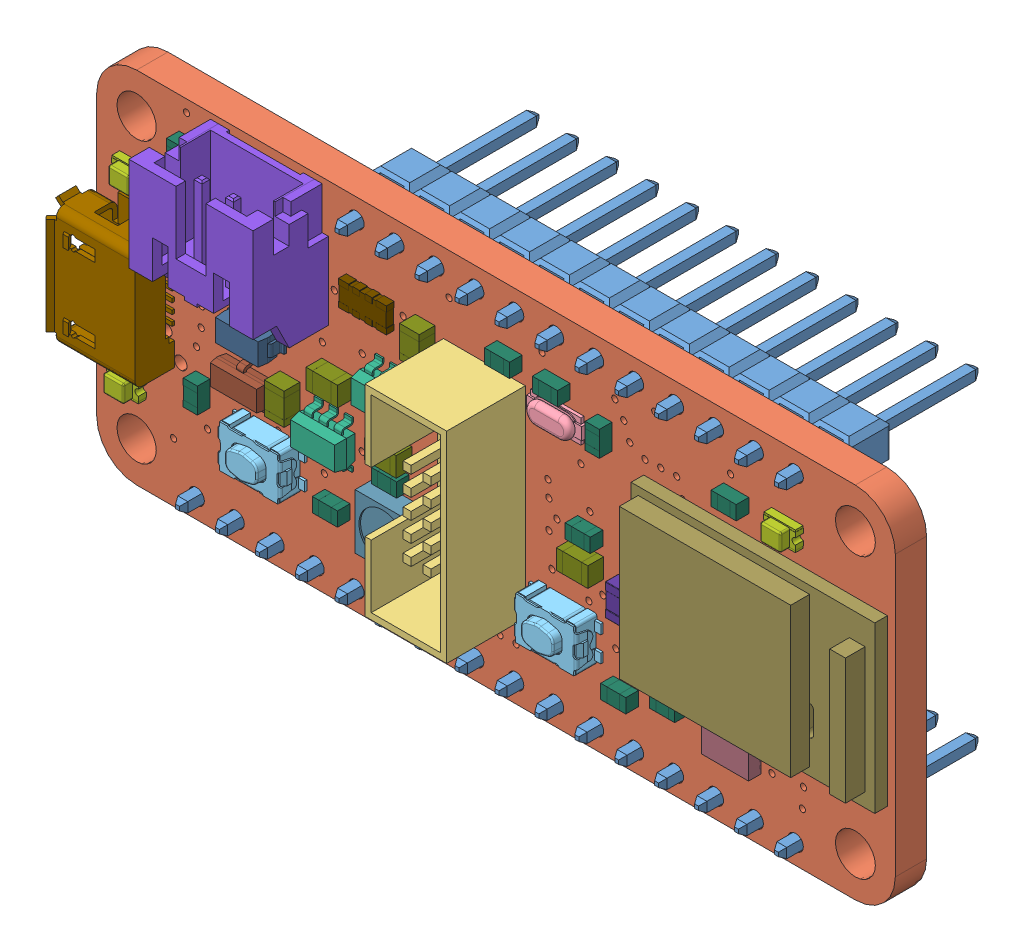
SolidWorks assembly nRF52840 Feather, configuration Default. Lengths in mm.
Overall size (51.45 22.86 16.48).
65 component instances, 18 part files, 10 mates.
Components (placement in the parent):
- Pin Header 1x1 TH Pitch 2.54mm^nRF52840 Feather-1: Pin Header 1x1 TH Pitch 2.54mm^nRF52840 Feather [Default] at (6.35 1.27 0.0014) x (0 1 0) z (0 0 -1) size (2.54 2.54 12.7) (virtual)
- Pin Header 1x1 TH Pitch 2.54mm^nRF52840 Feather-56: Pin Header 1x1 TH Pitch 2.54mm^nRF52840 Feather [Default] at (8.89 1.27 0.0014) x (0 1 0) z (0 0 -1) size (2.54 2.54 12.7) (virtual)
- Pin Header 1x1 TH Pitch 2.54mm^nRF52840 Feather-57: Pin Header 1x1 TH Pitch 2.54mm^nRF52840 Feather [Default] at (11.43 1.27 0.0014) x (0 1 0) z (0 0 -1) size (2.54 2.54 12.7) (virtual)
- Pin Header 1x1 TH Pitch 2.54mm^nRF52840 Feather-58: Pin Header 1x1 TH Pitch 2.54mm^nRF52840 Feather [Default] at (13.97 1.27 0.0014) x (0 1 0) z (0 0 -1) size (2.54 2.54 12.7) (virtual)
- Pin Header 1x1 TH Pitch 2.54mm^nRF52840 Feather-59: Pin Header 1x1 TH Pitch 2.54mm^nRF52840 Feather [Default] at (16.51 1.27 0.0014) x (0 1 0) z (0 0 -1) size (2.54 2.54 12.7) (virtual)
- Pin Header 1x1 TH Pitch 2.54mm^nRF52840 Feather-60: Pin Header 1x1 TH Pitch 2.54mm^nRF52840 Feather [Default] at (19.05 1.27 0.0014) x (0 1 0) z (0 0 -1) size (2.54 2.54 12.7) (virtual)
- Pin Header 1x1 TH Pitch 2.54mm^nRF52840 Feather-61: Pin Header 1x1 TH Pitch 2.54mm^nRF52840 Feather [Default] at (21.59 1.27 0.0014) x (0 1 0) z (0 0 -1) size (2.54 2.54 12.7) (virtual)
- Pin Header 1x1 TH Pitch 2.54mm^nRF52840 Feather-62: Pin Header 1x1 TH Pitch 2.54mm^nRF52840 Feather [Default] at (24.13 1.27 0.0014) x (0 1 0) z (0 0 -1) size (2.54 2.54 12.7) (virtual)
- Pin Header 1x1 TH Pitch 2.54mm^nRF52840 Feather-63: Pin Header 1x1 TH Pitch 2.54mm^nRF52840 Feather [Default] at (26.67 1.27 0.0014) x (0 1 0) z (0 0 -1) size (2.54 2.54 12.7) (virtual)
- Pin Header 1x1 TH Pitch 2.54mm^nRF52840 Feather-64: Pin Header 1x1 TH Pitch 2.54mm^nRF52840 Feather [Default] at (29.21 1.27 0.0014) x (0 1 0) z (0 0 -1) size (2.54 2.54 12.7) (virtual)
- Pin Header 1x1 TH Pitch 2.54mm^nRF52840 Feather-65: Pin Header 1x1 TH Pitch 2.54mm^nRF52840 Feather [Default] at (31.75 1.27 0.0014) x (0 1 0) z (0 0 -1) size (2.54 2.54 12.7) (virtual)
- Pin Header 1x1 TH Pitch 2.54mm^nRF52840 Feather-66: Pin Header 1x1 TH Pitch 2.54mm^nRF52840 Feather [Default] at (34.29 1.27 0.0014) x (0 1 0) z (0 0 -1) size (2.54 2.54 12.7) (virtual)
- Pin Header 1x1 TH Pitch 2.54mm^nRF52840 Feather-67: Pin Header 1x1 TH Pitch 2.54mm^nRF52840 Feather [Default] at (36.83 1.27 0.0014) x (0 1 0) z (0 0 -1) size (2.54 2.54 12.7) (virtual)
- Pin Header 1x1 TH Pitch 2.54mm^nRF52840 Feather-68: Pin Header 1x1 TH Pitch 2.54mm^nRF52840 Feather [Default] at (39.37 1.27 0.0014) x (0 1 0) z (0 0 -1) size (2.54 2.54 12.7) (virtual)
- Pin Header 1x1 TH Pitch 2.54mm^nRF52840 Feather-69: Pin Header 1x1 TH Pitch 2.54mm^nRF52840 Feather [Default] at (41.91 1.27 0.0014) x (0 1 0) z (0 0 -1) size (2.54 2.54 12.7) (virtual)
- Pin Header 1x1 TH Pitch 2.54mm^nRF52840 Feather-70: Pin Header 1x1 TH Pitch 2.54mm^nRF52840 Feather [Default] at (44.45 1.27 0.0014) x (0 1 0) z (0 0 -1) size (2.54 2.54 12.7) (virtual)
- Pin Header 1x1 TH Pitch 2.54mm^nRF52840 Feather-71: Pin Header 1x1 TH Pitch 2.54mm^nRF52840 Feather [Default] at (44.45 21.59 0.0014) x (0 -1 0) z (0 0 -1) size (2.54 2.54 12.7) (virtual)
- Pin Header 1x1 TH Pitch 2.54mm^nRF52840 Feather-72: Pin Header 1x1 TH Pitch 2.54mm^nRF52840 Feather [Default] at (41.91 21.59 0.0014) x (0 -1 0) z (0 0 -1) size (2.54 2.54 12.7) (virtual)
- Pin Header 1x1 TH Pitch 2.54mm^nRF52840 Feather-73: Pin Header 1x1 TH Pitch 2.54mm^nRF52840 Feather [Default] at (39.37 21.59 0.0014) x (0 -1 0) z (0 0 -1) size (2.54 2.54 12.7) (virtual)
- Pin Header 1x1 TH Pitch 2.54mm^nRF52840 Feather-74: Pin Header 1x1 TH Pitch 2.54mm^nRF52840 Feather [Default] at (36.83 21.59 0.0014) x (0 -1 0) z (0 0 -1) size (2.54 2.54 12.7) (virtual)
- Pin Header 1x1 TH Pitch 2.54mm^nRF52840 Feather-75: Pin Header 1x1 TH Pitch 2.54mm^nRF52840 Feather [Default] at (34.29 21.59 0.0014) x (0 -1 0) z (0 0 -1) size (2.54 2.54 12.7) (virtual)
- Pin Header 1x1 TH Pitch 2.54mm^nRF52840 Feather-76: Pin Header 1x1 TH Pitch 2.54mm^nRF52840 Feather [Default] at (31.75 21.59 0.0014) x (0 -1 0) z (0 0 -1) size (2.54 2.54 12.7) (virtual)
- Pin Header 1x1 TH Pitch 2.54mm^nRF52840 Feather-77: Pin Header 1x1 TH Pitch 2.54mm^nRF52840 Feather [Default] at (29.21 21.59 0.0014) x (0 -1 0) z (0 0 -1) size (2.54 2.54 12.7) (virtual)
- Pin Header 1x1 TH Pitch 2.54mm^nRF52840 Feather-78: Pin Header 1x1 TH Pitch 2.54mm^nRF52840 Feather [Default] at (26.67 21.59 0.0014) x (0 -1 0) z (0 0 -1) size (2.54 2.54 12.7) (virtual)
- Pin Header 1x1 TH Pitch 2.54mm^nRF52840 Feather-79: Pin Header 1x1 TH Pitch 2.54mm^nRF52840 Feather [Default] at (24.13 21.59 0.0014) x (0 -1 0) z (0 0 -1) size (2.54 2.54 12.7) (virtual)
- Pin Header 1x1 TH Pitch 2.54mm^nRF52840 Feather-80: Pin Header 1x1 TH Pitch 2.54mm^nRF52840 Feather [Default] at (21.59 21.59 0.0014) x (0 -1 0) z (0 0 -1) size (2.54 2.54 12.7) (virtual)
- Pin Header 1x1 TH Pitch 2.54mm^nRF52840 Feather-81: Pin Header 1x1 TH Pitch 2.54mm^nRF52840 Feather [Default] at (19.05 21.59 0.0014) x (0 -1 0) z (0 0 -1) size (2.54 2.54 12.7) (virtual)
- Pin Header 1x1 TH Pitch 2.54mm^nRF52840 Feather-82: Pin Header 1x1 TH Pitch 2.54mm^nRF52840 Feather [Default] at (16.51 21.59 0.0014) x (0 -1 0) z (0 0 -1) size (2.54 2.54 12.7) (virtual)
- 4062-nRF52830-Feather^nRF52840 Feather-1: 4062-nRF52830-Feather^nRF52840 Feather [Default] at origin size (51.45 22.86 6.99) (virtual)
  - PCB Component^4062-nRF52830-Feather_nRF52840 Feather-1: PCB Component^4062-nRF52830-Feather_nRF52840 Feather [Default] at origin size (51.45 22.86 6.99) (virtual)
    - Board^PCB Component_4062-nRF52830-Feather_nRF52840 Feather-1: Board^PCB Component_4062-nRF52830-Feather_nRF52840 Feather [Default] at origin size (50.8 22.86 1.99) (virtual)
    - 2x5 0.05_^PCB Component_4062-nRF52830-Feather_nRF52840 Feather-1: 2x5 0.05_^PCB Component_4062-nRF52830-Feather_nRF52840 Feather [Default] at (24.663 11.43 1.99) x (0 -1 0) z (0 0 1) size (12.8 5.2 5) (virtual)
    - 32.768^PCB Component_4062-nRF52830-Feather_nRF52840 Feather-1: 32.768^PCB Component_4062-nRF52830-Feather_nRF52840 Feather [Default] at (29.4 17.272 1.99) size (3.5 1.5 0.8) (virtual)
    - KMR2^PCB Component_4062-nRF52830-Feather_nRF52840 Feather-1: KMR2^PCB Component_4062-nRF52830-Feather_nRF52840 Feather [Default] at (11.1 6.223 1.99) size (4.6 2.8 1.94) (virtual)
    - KMR2^PCB Component_4062-nRF52830-Feather_nRF52840 Feather-2: KMR2^PCB Component_4062-nRF52830-Feather_nRF52840 Feather [Default] at (29.934 6.172 1.99) size (4.6 2.8 1.94) (virtual)
    - AP2112(3.3V)^PCB Component_4062-nRF52830-Feather_nRF52840 Feather-1: AP2112(3.3V)^PCB Component_4062-nRF52830-Feather_nRF52840 Feather [Default] at (15.138 9.144 1.99) x (-1 0 0) z (0 0 1) size (3 3 1.4) (virtual)
    - AP2112(3.3V)^PCB Component_4062-nRF52830-Feather_nRF52840 Feather-2: AP2112(3.3V)^PCB Component_4062-nRF52830-Feather_nRF52840 Feather [Default] at (18.974 13.386 1.99) x (-1 0 0) z (0 0 1) size (3 3 1.4) (virtual)
    - BLUE^PCB Component_4062-nRF52830-Feather_nRF52840 Feather-1: BLUE^PCB Component_4062-nRF52830-Feather_nRF52840 Feather [Default] at (2.083 5.639 1.99) x (0 -1 0) z (0 0 1) size (1.25 2.02 1.1) (virtual)
    - BLUE^PCB Component_4062-nRF52830-Feather_nRF52840 Feather-2: BLUE^PCB Component_4062-nRF52830-Feather_nRF52840 Feather [Default] at (2.54 17.272 1.99) x (0 1 0) z (0 0 1) size (1.25 2.02 1.1) (virtual)
    - BLUE^PCB Component_4062-nRF52830-Feather_nRF52840 Feather-3: BLUE^PCB Component_4062-nRF52830-Feather_nRF52840 Feather [Default] at (44.006 18.352 1.99) x (0 1 0) z (0 0 1) size (1.25 2.02 1.1) (virtual)
    - JSTPH^PCB Component_4062-nRF52830-Feather_nRF52840 Feather-1: JSTPH^PCB Component_4062-nRF52830-Feather_nRF52840 Feather [Default] at (10.795 19.304 1.99) size (7.9 8.6 4.8) (virtual)
    - 4u20329^PCB Component_4062-nRF52830-Feather_nRF52840 Feather-1: 4u20329^PCB Component_4062-nRF52830-Feather_nRF52840 Feather [Default] at (4.445 11.43 1.99) x (0 -1 0) z (0 0 1) size (8.8 5.6 3) (virtual)
    - MBR120^PCB Component_4062-nRF52830-Feather_nRF52840 Feather-1: MBR120^PCB Component_4062-nRF52830-Feather_nRF52840 Feather [Default] at (10.262 12.395 1.99) x (-1 0 0) z (0 0 1) size (3.6 1.4 1.35) (virtual)
    - DMG2305^PCB Component_4062-nRF52830-Feather_nRF52840 Feather-1: DMG2305^PCB Component_4062-nRF52830-Feather_nRF52840 Feather [Default] at (9.817 9.55 1.99) size (3.04 2.64 1.12) (virtual)
    - MDBT50^PCB Component_4062-nRF52830-Feather_nRF52840 Feather-1: MDBT50^PCB Component_4062-nRF52830-Feather_nRF52840 Feather [Default] at (42.545 11.43 1.99) x (0 -1 0) z (0 0 1) size (10.5 15.5 2.05) (virtual)
    - GD25Q16^PCB Component_4062-nRF52830-Feather_nRF52840 Feather-1: GD25Q16^PCB Component_4062-nRF52830-Feather_nRF52840 Feather [Default] at (40.767 4.953 1.99) x (-1 0 0) z (0 0 1) size (3 2 0.8) (virtual)
    - WS2812B3535^PCB Component_4062-nRF52830-Feather_nRF52840 Feather-1: WS2812B3535^PCB Component_4062-nRF52830-Feather_nRF52840 Feather [Default] at (19.387 6.145 1.99) x (-1 0 0) z (0 0 1) size (3.5 3.5 1.2) (virtual)
    - 0.1uF^PCB Component_4062-nRF52830-Feather_nRF52840 Feather-1: 0.1uF^PCB Component_4062-nRF52830-Feather_nRF52840 Feather [Default] at (19.075 8.788 1.99) size (1.6 0.9 0.8) (virtual)
    - 0.1uF^PCB Component_4062-nRF52830-Feather_nRF52840 Feather-2: 0.1uF^PCB Component_4062-nRF52830-Feather_nRF52840 Feather [Default] at (29.312 18.936 1.99) x (-1 0 0) z (0 0 1) size (1.6 0.9 0.8) (virtual)
    - 0.1uF^PCB Component_4062-nRF52830-Feather_nRF52840 Feather-3: 0.1uF^PCB Component_4062-nRF52830-Feather_nRF52840 Feather [Default] at (26.264 18.974 1.99) x (-1 0 0) z (0 0 1) size (1.6 0.9 0.8) (virtual)
    - 0.1uF^PCB Component_4062-nRF52830-Feather_nRF52840 Feather-4: 0.1uF^PCB Component_4062-nRF52830-Feather_nRF52840 Feather [Default] at (31.394 11.9 1.99) size (1.6 0.9 0.8) (virtual)
    - 0.1uF^PCB Component_4062-nRF52830-Feather_nRF52840 Feather-5: 0.1uF^PCB Component_4062-nRF52830-Feather_nRF52840 Feather [Default] at (5.69 20.053 1.99) x (0 -1 0) z (0 0 1) size (1.6 0.9 0.8) (virtual)
    - 0.1uF^PCB Component_4062-nRF52830-Feather_nRF52840 Feather-6: 0.1uF^PCB Component_4062-nRF52830-Feather_nRF52840 Feather [Default] at (40.678 18.339 1.99) x (-1 0 0) z (0 0 1) size (1.6 0.9 0.8) (virtual)
    - 0.1uF^PCB Component_4062-nRF52830-Feather_nRF52840 Feather-7: 0.1uF^PCB Component_4062-nRF52830-Feather_nRF52840 Feather [Default] at (6.756 7.379 1.99) x (0 1 0) z (0 0 1) size (1.6 0.9 0.8) (virtual)
    - 0.1uF^PCB Component_4062-nRF52830-Feather_nRF52840 Feather-8: 0.1uF^PCB Component_4062-nRF52830-Feather_nRF52840 Feather [Default] at (15.316 5.309 1.99) size (1.6 0.9 0.8) (virtual)
    - 0.1uF^PCB Component_4062-nRF52830-Feather_nRF52840 Feather-9: 0.1uF^PCB Component_4062-nRF52830-Feather_nRF52840 Feather [Default] at (33.655 4.191 1.99) size (1.6 0.9 0.8) (virtual)
    - 0.1uF^PCB Component_4062-nRF52830-Feather_nRF52840 Feather-10: 0.1uF^PCB Component_4062-nRF52830-Feather_nRF52840 Feather [Default] at (36.766 5.27 1.99) size (1.6 0.9 0.8) (virtual)
    - 0.1uF^PCB Component_4062-nRF52830-Feather_nRF52840 Feather-11: 0.1uF^PCB Component_4062-nRF52830-Feather_nRF52840 Feather [Default] at (32.322 17.78 1.99) x (0 1 0) z (0 0 1) size (1.6 0.9 0.8) (virtual)
    - 10uF^PCB Component_4062-nRF52830-Feather_nRF52840 Feather-1: 10uF^PCB Component_4062-nRF52830-Feather_nRF52840 Feather [Default] at (19.05 10.249 1.99) size (2 1.25 1) (virtual)
    - 10uF^PCB Component_4062-nRF52830-Feather_nRF52840 Feather-2: 10uF^PCB Component_4062-nRF52830-Feather_nRF52840 Feather [Default] at (20.892 17.272 1.99) x (0 1 0) z (0 0 1) size (2 1.25 1) (virtual)
    - 10uF^PCB Component_4062-nRF52830-Feather_nRF52840 Feather-3: 10uF^PCB Component_4062-nRF52830-Feather_nRF52840 Feather [Default] at (12.294 9.855 1.99) x (0 1 0) z (0 0 1) size (2 1.25 1) (virtual)
    - 10uF^PCB Component_4062-nRF52830-Feather_nRF52840 Feather-4: 10uF^PCB Component_4062-nRF52830-Feather_nRF52840 Feather [Default] at (31.242 10.274 1.99) size (2 1.25 1) (virtual)
    - 10uF^PCB Component_4062-nRF52830-Feather_nRF52840 Feather-5: 10uF^PCB Component_4062-nRF52830-Feather_nRF52840 Feather [Default] at (15.316 12.256 1.99) x (-1 0 0) z (0 0 1) size (2 1.25 1) (virtual)
    - DNP^PCB Component_4062-nRF52830-Feather_nRF52840 Feather-1: DNP^PCB Component_4062-nRF52830-Feather_nRF52840 Feather [Default] at (33.82 9.436 1.99) x (0 -1 0) z (0 0 1) size (2 1.25 0.85) (virtual)
    - 100K^PCB Component_4062-nRF52830-Feather_nRF52840 Feather-1: 100K^PCB Component_4062-nRF52830-Feather_nRF52840 Feather [Default] at (17.374 17.501 1.99) x (-1 0 0) z (0 0 1) size (3.05 1.6 0.5) (virtual)
Mates (geometry in assembly coordinates):
- Width1: width: plane of Pin Header 1x1 TH Pitch 2.54mm^nRF52840 Feather-1 through (5.08 0.327 0.028) normal (-1 0 0); plane of Pin Header 1x1 TH Pitch 2.54mm^nRF52840 Feather-1 through (7.62 0.327 0.028) normal (1 0 0); cylinder of 4062-nRF52830-Feather^nRF52840 Feather-1/PCB Component^4062-nRF52830-Feather_nRF52840 Feather-1/Board^PCB Component_4062-nRF52830-Feather_nRF52840 Feather-1 through (6.35 1.27 0) axis (0 0 1) radius 0.5
- Width2: width: plane of Pin Header 1x1 TH Pitch 2.54mm^nRF52840 Feather-1 through (5.407 2.54 -2.4727) normal (0 1 0); plane of Pin Header 1x1 TH Pitch 2.54mm^nRF52840 Feather-1 through (5.407 0 -2.4727) normal (0 -1 0); cylinder of 4062-nRF52830-Feather^nRF52840 Feather-1/PCB Component^4062-nRF52830-Feather_nRF52840 Feather-1/Board^PCB Component_4062-nRF52830-Feather_nRF52840 Feather-1 through (6.35 1.27 0) axis (0 0 1) radius 0.5
- Coincident5: coincident anti-aligned: plane of 4062-nRF52830-Feather^nRF52840 Feather-1/PCB Component^4062-nRF52830-Feather_nRF52840 Feather-1/Board^PCB Component_4062-nRF52830-Feather_nRF52840 Feather-1 through (25.4 11.43 0) normal (0 0 -1); plane of Pin Header 1x1 TH Pitch 2.54mm^nRF52840 Feather-1 through (5.07 0.473 0) normal (0 0 1)
- Width3: width: plane of Pin Header 1x1 TH Pitch 2.54mm^nRF52840 Feather-1 through (5.08 0.327 0.028) normal (-1 0 0); plane of 4062-nRF52830-Feather.step-2/Copy of nRFBoard^4062-nRF52830-Feather.step-1 through (7.62 0.327 0.028) normal (1 0 0); cylinder of Pin Header 1x1 TH Pitch 2.54mm^nRF52840 Feather-1 through (6.35 1.27 0) axis (0 0 1) radius 0.5
- Width4: width: plane of Pin Header 1x1 TH Pitch 2.54mm^nRF52840 Feather-1 through (5.407 2.54 -2.4727) normal (0 1 0); plane of 4062-nRF52830-Feather.step-2/Copy of nRFBoard^4062-nRF52830-Feather.step-1 through (5.407 0 -2.4727) normal (0 -1 0); cylinder of Pin Header 1x1 TH Pitch 2.54mm^nRF52840 Feather-1 through (6.35 1.27 0) axis (0 0 1) radius 0.5
- Parallel2: parallel aligned: plane of Pin Header 1x1 TH Pitch 2.54mm^nRF52840 Feather-1 through (5.407 0 -2.4727) normal (0 -1 0); plane of 4062-nRF52830-Feather.step-2/Copy of nRFBoard^4062-nRF52830-Feather.step-1 through (2.54 0 0) normal (0 -1 0)
- Coincident6: coincident anti-aligned: plane of 4062-nRF52830-Feather.step-2/Copy of nRFBoard^4062-nRF52830-Feather.step-1 through (25.4 11.43 0) normal (0 0 -1)
- Coincident7: coincident anti-aligned: plane of 4062-nRF52830-Feather.step-2/Copy of nRFBoard^4062-nRF52830-Feather.step-1 through (0 9.144 0) normal (-1 0 0)
- Coincident8: coincident anti-aligned: plane of 4062-nRF52830-Feather.step-2/Copy of nRFBoard^4062-nRF52830-Feather.step-1 through (2.54 0 0) normal (0 -1 0)
- Parallel3: parallel aligned: plane of Pin Header 1x1 TH Pitch 2.54mm^nRF52840 Feather-1 through (5.407 0 -2.4727) normal (0 -1 0); plane of 4062-nRF52830-Feather^nRF52840 Feather-1/PCB Component^4062-nRF52830-Feather_nRF52840 Feather-1/Board^PCB Component_4062-nRF52830-Feather_nRF52840 Feather-1 through (2.54 0 0) normal (0 -1 0)
